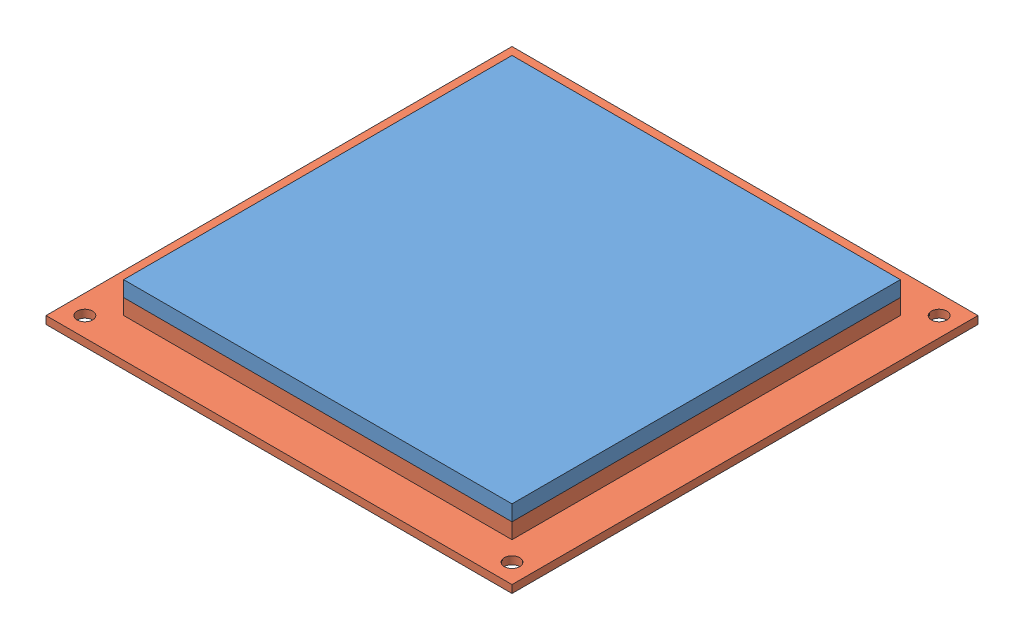
SolidWorks assembly Top_Bottom_Assembly_New, configuration Default. Lengths in mm.
Overall size (152.4 12.7 152.4).
2 component instances, 2 part files, 3 mates.
Components (placement in the parent):
- 440_Top_New_V2-2: 440_Top_New_V2 [Default] at (112.339 42.2615 62.8698) x (1 0 0) z (0 -1 0) size (127 127 10.16)
- 440_Bottom_New_V2-2: 440_Bottom_New_V2 [Default] at (112.339 37.1815 62.8698) size (152.4 7.62 152.4)
Mates (geometry in assembly coordinates):
- Coincident4: coincident: plane of 440_Top_New_V2-2 through (112.339 37.1815 62.8698) normal (0 -1 0); plane of 440_Bottom_New_V2-2 through (112.339 37.1815 62.8698) normal (0 1 0)
- Coincident5: coincident: line of 440_Top_New_V2-2 through (175.839 42.2615 -0.6302) axis (0 0 1); line of 440_Bottom_New_V2-2 through (175.839 42.2615 126.3698) axis (0 0 -1)
- Coincident6: coincident anti-aligned: line of 440_Top_New_V2-2 through (48.839 42.2615 -0.6302) axis (1 0 0); line of 440_Bottom_New_V2-2 through (175.839 42.2615 -0.6302) axis (-1 0 0)
